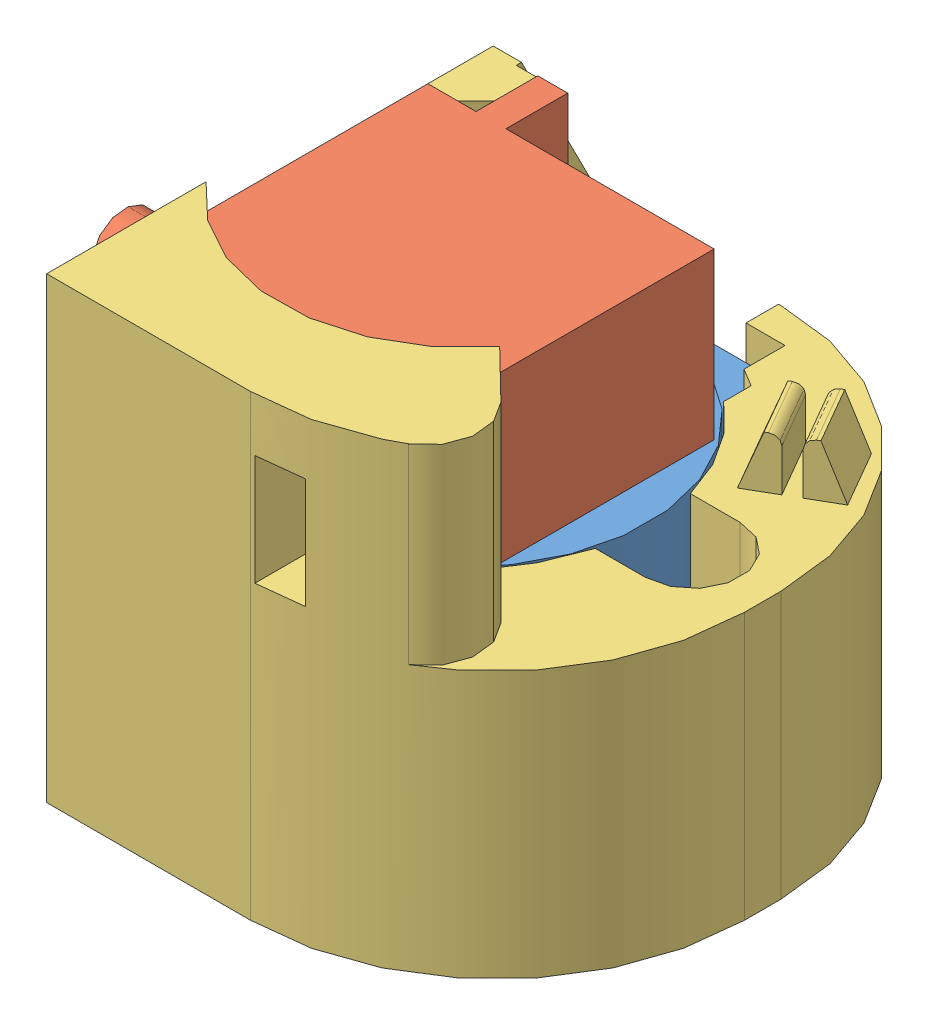
SolidWorks assembly Shoulder, configuration Default. Lengths in mm.
Overall size (44.65 43.7 40.8).
3 component instances, 3 part files, 5 mates.
Components (placement in the parent):
- StepperMotor-1: StepperMotor [Default] at origin size (42 29 31)
- SG92rMicroServo-1: SG92rMicroServo [Alignment] at (11 25.35 3.1) x (0 0 1) z (-1 0 0) size (32 12.7 29.2)
- BaseShoulder-1: BaseShoulder [Default] at origin size (34.65 35.2 40.8)
Mates (geometry in assembly coordinates):
- Parallel1: parallel aligned: plane of StepperMotor-1 through (7.3 16.5 -17) normal (0 0 -1); plane of SG92rMicroServo-1 through (-11 19 -8.15) normal (0 0 -1)
- Perpendicular1: perpendicular: cylinder of StepperMotor-1 through (0 -4 8) axis (0 1 0) radius 2.5; cylinder of SG92rMicroServo-1 through (-54.4711 25.35 8) axis (1 0 0) radius 2.5
- Coincident3: coincident anti-aligned: plane of StepperMotor-1 through (0 19 0) normal (0 1 0); plane of SG92rMicroServo-1 through (-11 19 -8.15) normal (0 -1 0)
- Coincident5: coincident aligned: plane of StepperMotor-1 through (-7.3 16.5 -17) normal (-1 0 0); plane of SG92rMicroServo-1 through (-7.3 25.35 3.1) normal (-1 0 0)
- Tangent3: tangent aligned: cylinder of SG92rMicroServo-1 through (-54.4711 25.35 8) axis (1 0 0) radius 2.5
